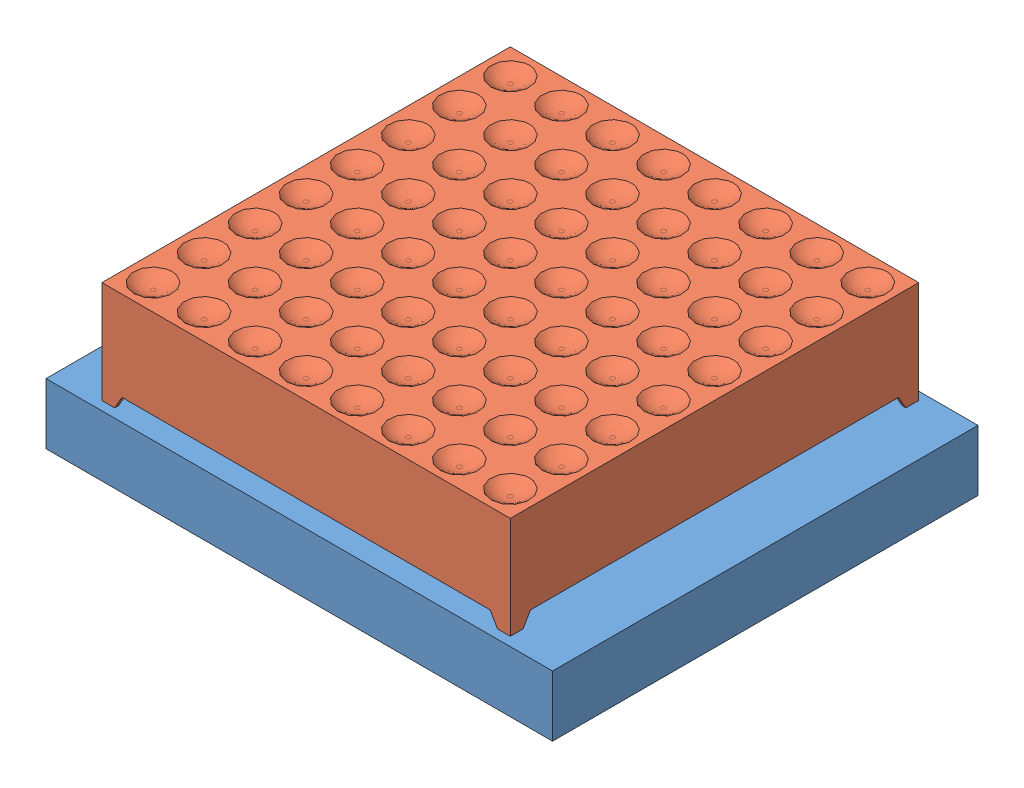
SolidWorks assembly Assem1, configuration Default. Lengths in mm.
Overall size (39.69 12.76 33.34).
2 component instances, 2 part files, 6 mates.
Components (placement in the parent):
- LEDbackpack-1: LEDbackpack [Default] at (14.4644 16.8017 31.6864) size (39.69 4.76 33.34)
- LED Matrix-1: LED Matrix [?] at (14.2971 25.5642 31.6526) x (-1 0 0) z (0 0 -1) size (32 12.5 32)
Mates (geometry in assembly coordinates):
- Coincident1: coincident: plane of LEDbackpack-1 through (14.4644 21.5642 31.6864) normal (0 1 0); plane of LED Matrix-1 through (-1.7029 21.5642 47.7811) normal (0 -1 0)
- Coincident3: coincident: plane of LEDbackpack-1 through (14.4644 21.5642 31.6864) normal (0 1 0); plane of LED Matrix-1 through (-1.7029 21.5642 47.7811) normal (0 -1 0)
- Coincident4: coincident: plane of LEDbackpack-1 through (14.4644 21.5642 31.6864) normal (0 1 0); plane of LED Matrix-1 through (-1.7029 21.5642 47.7811) normal (0 -1 0)
- Coincident5: coincident: plane of LEDbackpack-1 through (14.4644 21.5642 31.6864) normal (0 1 0); plane of LED Matrix-1 through (-1.7029 21.5642 47.7811) normal (0 -1 0)
- Distance1: distance = 3.81 mm: line of LED Matrix-1 through (-1.7029 22.5642 17.23) axis (0 0 1); line of LEDbackpack-1 through (-5.3794 21.5642 15.0176) axis (0 0 1)
- Distance3: distance = 0.635 mm aligned: plane of LED Matrix-1 through (30.2971 29.5642 15.6526) normal (0 0 -1); plane of LEDbackpack-1 through (-5.3794 21.5642 15.0176) normal (0 0 -1)
